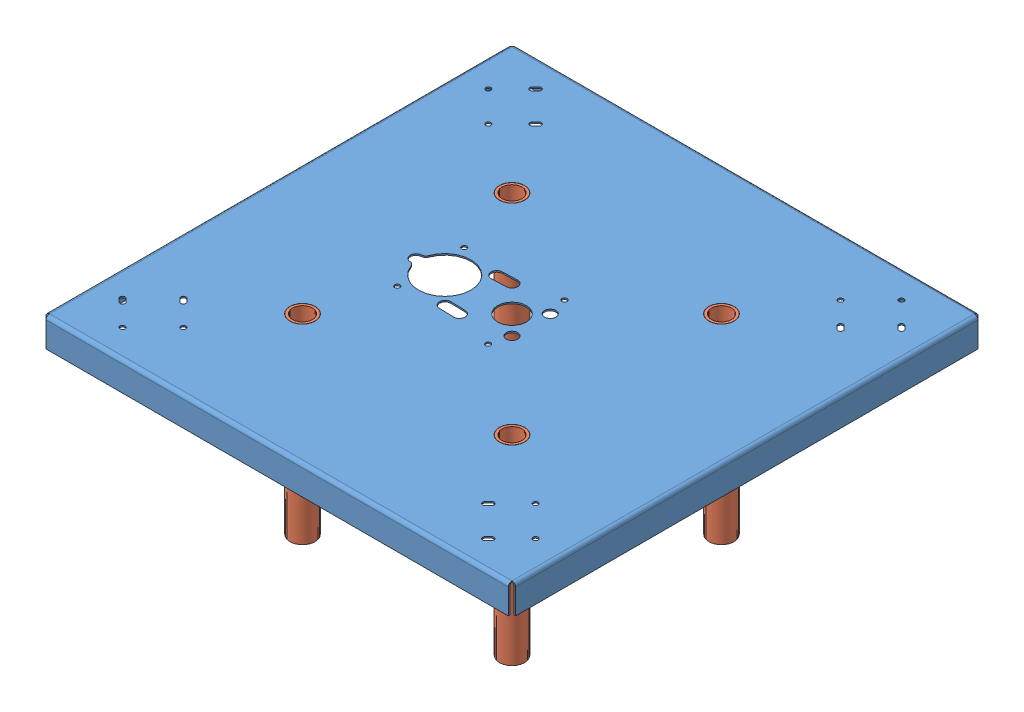
SolidWorks assembly GE-22356, configuration Corners. Lengths in mm.
Overall size (624.05 254 624.05).
5 component instances, 2 part files, 11 mates.
Components (placement in the parent):
- GE-22356-01-1: GE-22356-01 [Default] at (0 -1.9844 0)
- GE-22356-02-1: GE-22356-02 [Default] at (-139.192 -254 139.192)
- GE-22356-02-2: GE-22356-02 [Default] at (-139.192 -254 -139.192)
- GE-22356-02-3: GE-22356-02 [Default] at (139.192 -254 -139.192)
- GE-22356-02-4: GE-22356-02 [Default] at (139.192 -254 139.192)
Mates (geometry in assembly coordinates):
- Coincident1: coincident aligned: plane of GE-22356-01-1 through (0 -1.9844 0) normal (0 0 1)
- Coincident2: coincident aligned: plane of GE-22356-01-1 through (0 -1.9844 0) normal (1 0 0)
- Coincident3: coincident aligned: plane of GE-22356-01-1 through (0 0 0) normal (0 1 0)
- Concentric1: concentric anti-aligned: cylinder of GE-22356-02-2 through (-139.192 0 -139.192) axis (0 -1 0) radius 16.7005; cylinder of GE-22356-01-1 through (-139.192 0 -139.192) axis (0 1 0) radius 16.891
- Concentric2: concentric anti-aligned: cylinder of GE-22356-02-3 through (139.192 0 -139.192) axis (0 -1 0) radius 16.7005; cylinder of GE-22356-01-1 through (139.192 0 -139.192) axis (0 1 0) radius 16.891
- Concentric3: concentric anti-aligned: cylinder of GE-22356-02-4 through (139.192 0 139.192) axis (0 -1 0) radius 16.7005; cylinder of GE-22356-01-1 through (139.192 0 139.192) axis (0 1 0) radius 16.891
- Concentric4: concentric anti-aligned: cylinder of GE-22356-02-1 through (-139.192 0 139.192) axis (0 -1 0) radius 16.7005; cylinder of GE-22356-01-1 through (-139.192 0 139.192) axis (0 1 0) radius 16.891
- Coincident4: coincident aligned: plane of GE-22356-01-1 through (0 0 0) normal (0 1 0); plane of GE-22356-02-1 through (-139.192 0 139.192) normal (0 1 0)
- Coincident5: coincident aligned: plane of GE-22356-01-1 through (0 0 0) normal (0 1 0); plane of GE-22356-02-4 through (139.192 0 139.192) normal (0 1 0)
- Coincident6: coincident aligned: plane of GE-22356-01-1 through (0 0 0) normal (0 1 0); plane of GE-22356-02-3 through (139.192 0 -139.192) normal (0 1 0)
- Coincident7: coincident aligned: plane of GE-22356-01-1 through (0 0 0) normal (0 1 0); plane of GE-22356-02-2 through (-139.192 0 -139.192) normal (0 1 0)
